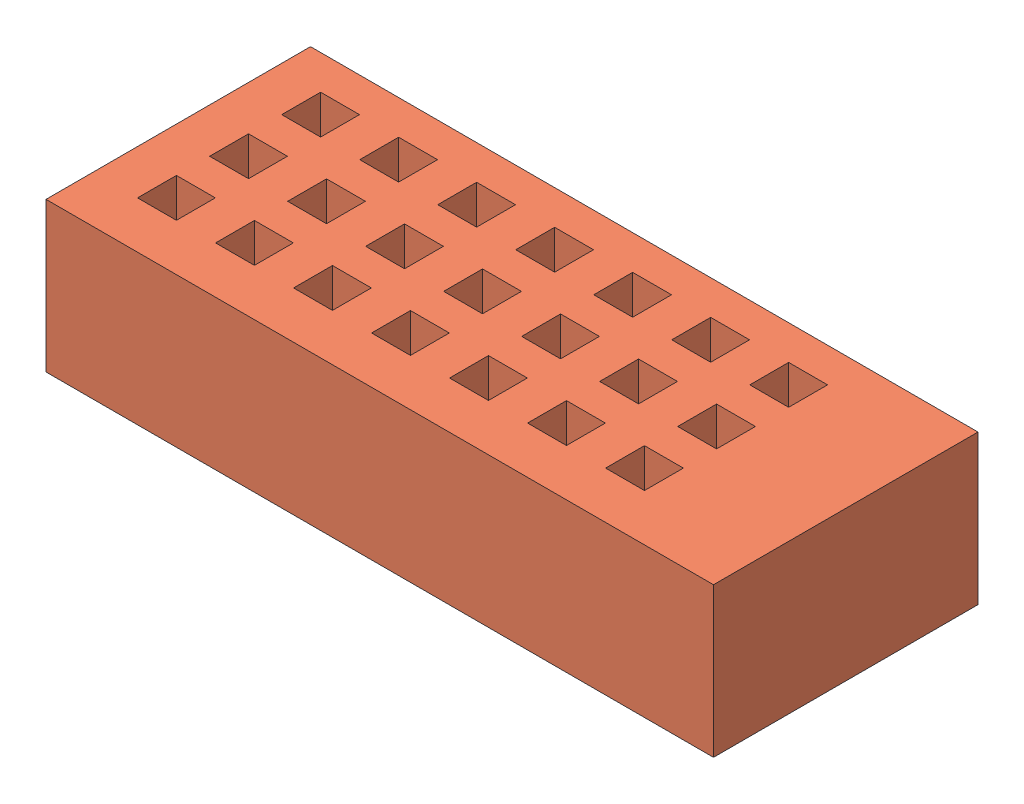
SolidWorks assembly MaytagController, configuration Default. Lengths in mm.
Overall size (47.62 11.94 18.87).
3 component instances, 3 part files, 4 mates.
Components (placement in the parent):
- MaytagSocket-1: MaytagSocket [Default] at origin size (41.78 8.13 10.74)
- ArduinoPin-1: ArduinoPin [Default] at (2.52 22.128 0.5798) x (-1 0 0) z (0 0 1) size (2.52 20 2.52) (hidden)
- MaytagAdapter-1: MaytagAdapter [Default] at origin size (47.62 10.67 18.87)
Mates (geometry in assembly coordinates):
- Coincident2: coincident anti-aligned: plane of MaytagSocket-1 through (0 8.128 0) normal (0 1 0); plane of ArduinoPin-1 through (2.52 8.128 0.5798) normal (0 -1 0)
- Parallel1: parallel aligned: plane of MaytagSocket-1 through (0 8.128 0) normal (0 0 1); plane of ArduinoPin-1 through (2.52 8.128 0.5798) normal (0 0 1)
- Distance1: distance = 0.254 mm anti-aligned: plane of MaytagSocket-1 through (0 8.128 -0.5842) normal (0 0 -1); cylinder of ArduinoPin-1 through (1.26 2.128 -0.6802) axis (0 1 0) radius 0.35
- Coincident4: coincident aligned: plane of MaytagSocket-1 through (0 8.128 0) normal (-1 0 0); plane of ArduinoPin-1 through (0 8.128 0.5798) normal (-1 0 0)
